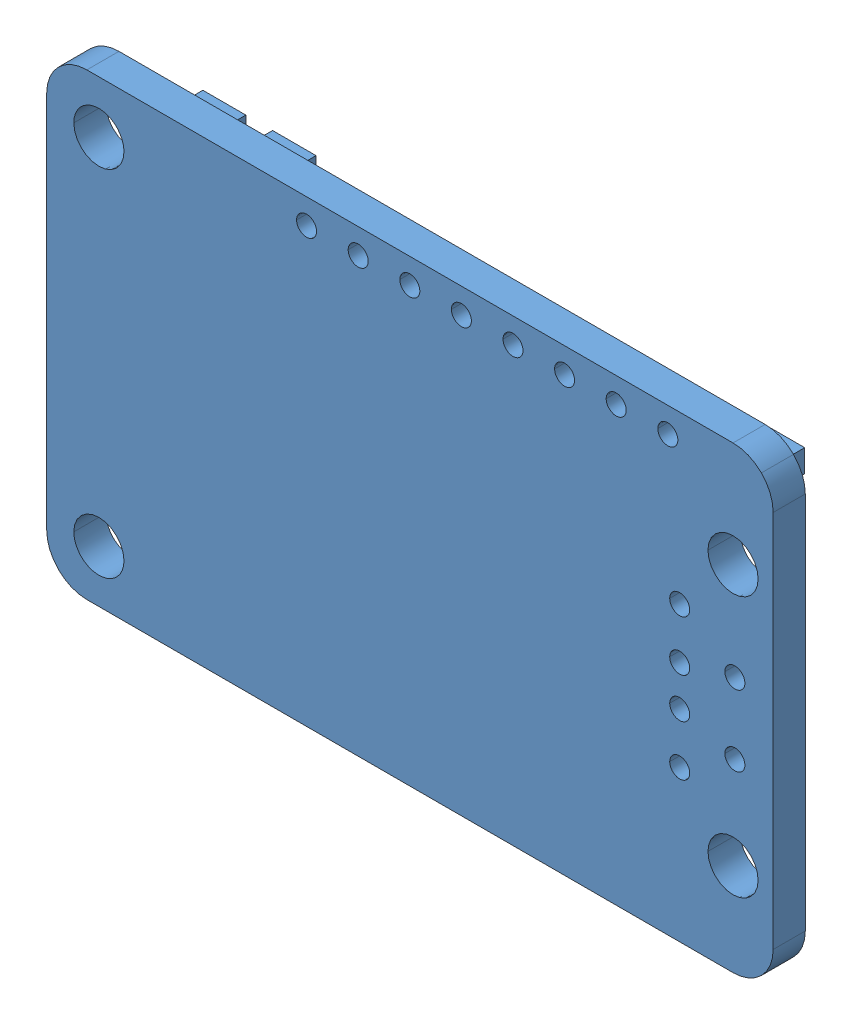
SolidWorks assembly powerboost 1000c.f3d v3, configuration Default. Lengths in mm.
Overall size (36.91 23.37 4.38).
4 component instances, 2 part files, 0 mates.
Components (placement in the parent):
- powerboost 1000c.f3d v3.stp-1: powerboost 1000c.f3d v3.stp [Default] at origin size (36.91 23.37 4.38)
  - Product_Powerboost1000.stp-1: Product_Powerboost1000.stp [Default] at (136.767 14.3916 -6.9613) x (0.007037 -0.999975 0) z (0.000013 0 1) size (23.11 36.75 4.38)
    - powerboost 1000c.f3d v3.stp-1: powerboost 1000c.f3d v3.stp [Default] at (52.9166 -138.643 19.3595) x (0.007037 0.999975 0.000013) z (0 0.000013 -1) size (36.2 22.86 4.11)
    - molex_0473460001.stp-1: molex_0473460001.stp [Default] at (41.472 -136.4124 19.5663) x (-0.999975 0.007037 0) z (-0.007037 -0.999975 -0.000013) size (8.25 3.45 5.94)
